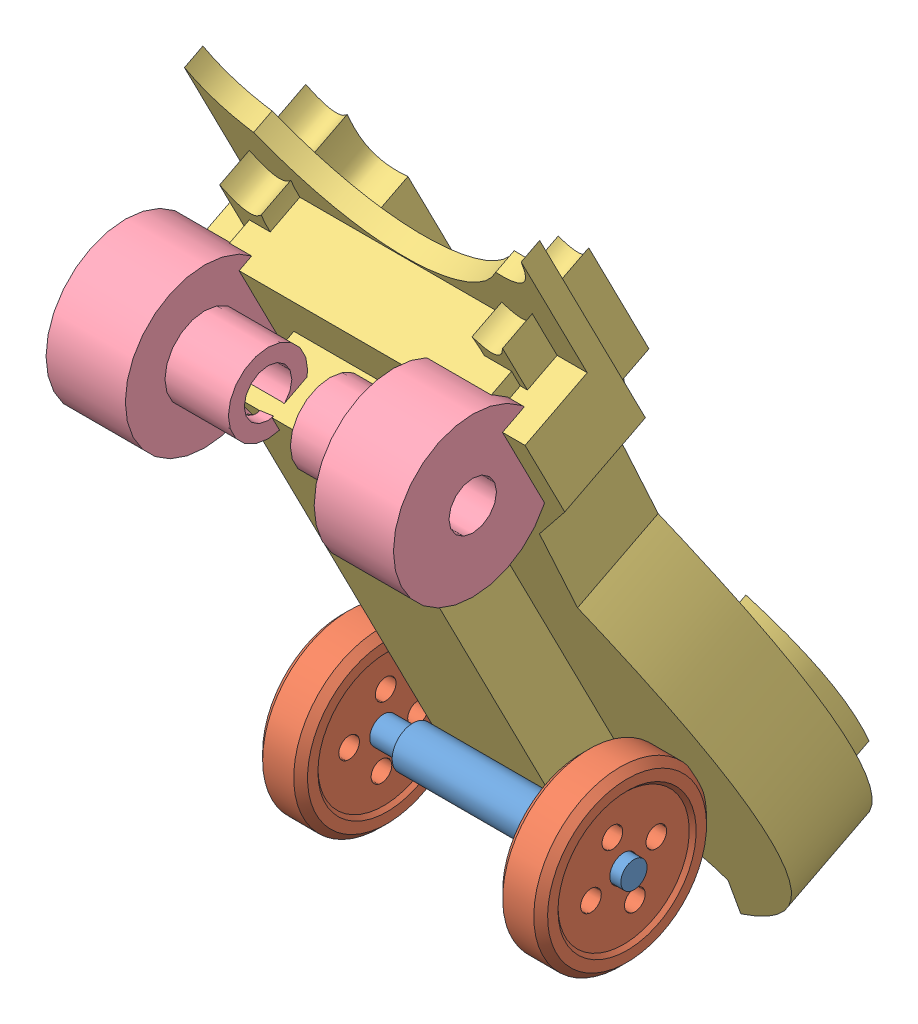
SolidWorks assembly final design, configuration Default. Lengths in mm.
Overall size (1101.98 2400.62 1603.92).
7 component instances, 4 part files, 3 mates.
Components (placement in the parent):
- front assmbly-1: front assmbly [Default] at (-152.2965 37.2657 62.7686) size (844.88 635.56 635.56)
  - Part2-1: Part2 [Default] at (292.0461 432.0687 660.3918) size (840 120 120)
  - wheel + tire-1: wheel + tire [Default] at (627.0952 432.0687 660.3918) x (0 -0.325618 0.945501) z (-1 0 0) size (500 500 130)
  - wheel + tire-2: wheel + tire [Default] at (-67.832 432.0687 660.3918) x (0 -0.060971 -0.99814) z (1 0 0) size (500 500 130)
- chassis finalll-1: chassis finalll [Default] at (141.2825 1001.6384 601.8439) x (0 0.890041 0.45588) z (0 -0.45588 0.890041) size (2405.16 1101.98 570.15)
- wheel big updated-1: wheel big updated [Default] at (-242.9789 1673.7026 1249.5804) x (0 0 1) z (-1 0 0) size (459 459 413.1)
- wheel big updated-2: wheel big updated [Default] at (437.277 1648.949 1210.7323) x (0 0 -1) z (1 0 0) size (459 459 413.1)
Mates (geometry in assembly coordinates):
- Tangent10: tangent: cylinder of front assmbly-1/Part2-1 through (359.7495 469.3344 723.1604) axis (-1 0 0) radius 60; plane of chassis finalll-1 through (85.3399 554.1096 699.1698) normal (0 -0.45588 0.890041)
- Tangent11: tangent: cylinder of front assmbly-1/Part2-1 through (359.7495 469.3344 723.1604) axis (-1 0 0) radius 60; plane of chassis finalll-1 through (85.3399 638.207 534.9815) normal (0 -0.45588 0.890041)
- Coincident15: coincident: point of chassis finalll-1; curve of wheel big updated-1
